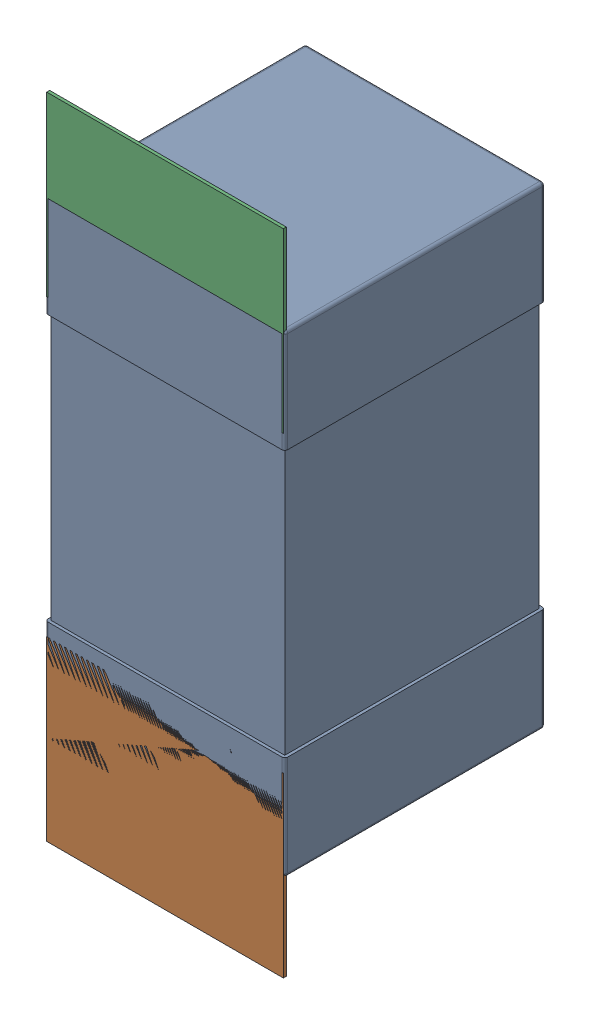
SolidWorks assembly C105, configuration Défaut. Lengths in mm.
Overall size (0.81 2.19 0.88).
5 component instances, 2 part files, 0 mates.
Components (placement in the parent):
- 0603_C-1: 0603_C [Défaut] at (9.779 -9.4544 -2.0818) x (0 1 0) z (0 0 -1) size (1.6 0.81 0.88)
- 8260087904-1: 8260087904 [Défaut] at (9.779 -9.7993 -2.0918) size (0.8 0.6 0.01)
  - Extruded_1211-1: Extruded_1211 [Défaut] at origin size (0.8 0.6 0.01)
- 8260087904-2: 8260087904 [Défaut] at (9.779 -8.2044 -2.0918) size (0.8 0.6 0.01)
  - Extruded_1211-1: Extruded_1211 [Défaut] at origin size (0.8 0.6 0.01)
